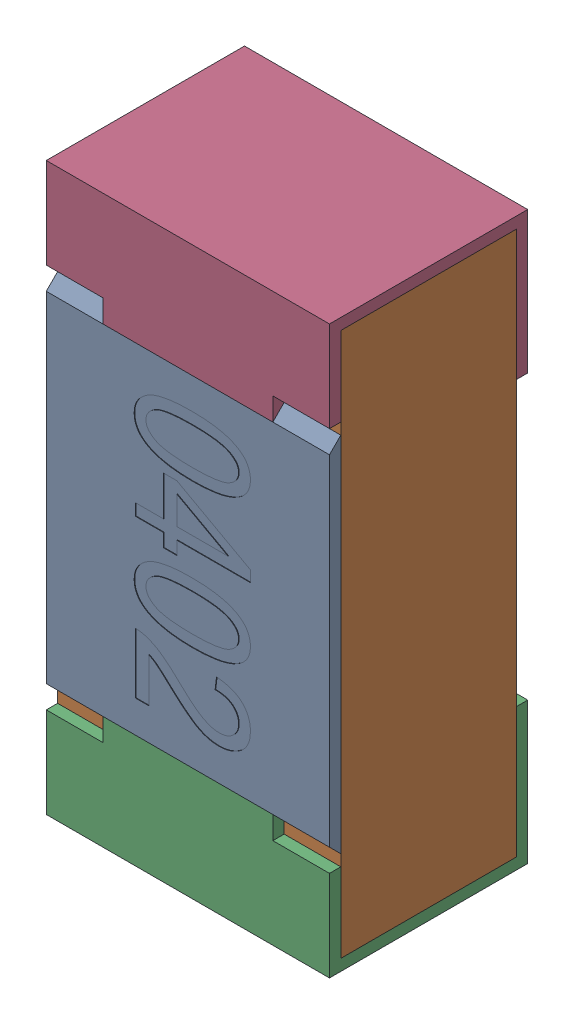
SolidWorks assembly R30, configuration Standard. Lengths in mm.
Overall size (0.5 1 0.35).
5 component instances, 4 part files, 0 mates.
Components (placement in the parent):
- R30-subassembly-1-1: R30-subassembly-1 [Standard] at (-14.4 1.3999 0) x (0 -1 0) z (0 0 1) size (1 0.5 0.35)
  - User Library-R_0402-1: User Library-R_0402 [Standard] at origin size (0.64 0.5 0.02)
  - User Library-R_0402-1-1: User Library-R_0402-1 [Standard] at origin size (0.96 0.5 0.31)
  - User Library-R_0402-2-1: User Library-R_0402-2 [Standard] at origin size (0.25 0.5 0.35)
  - User Library-R_0402-3-1: User Library-R_0402-3 [Standard] at origin size (0.25 0.5 0.35)
